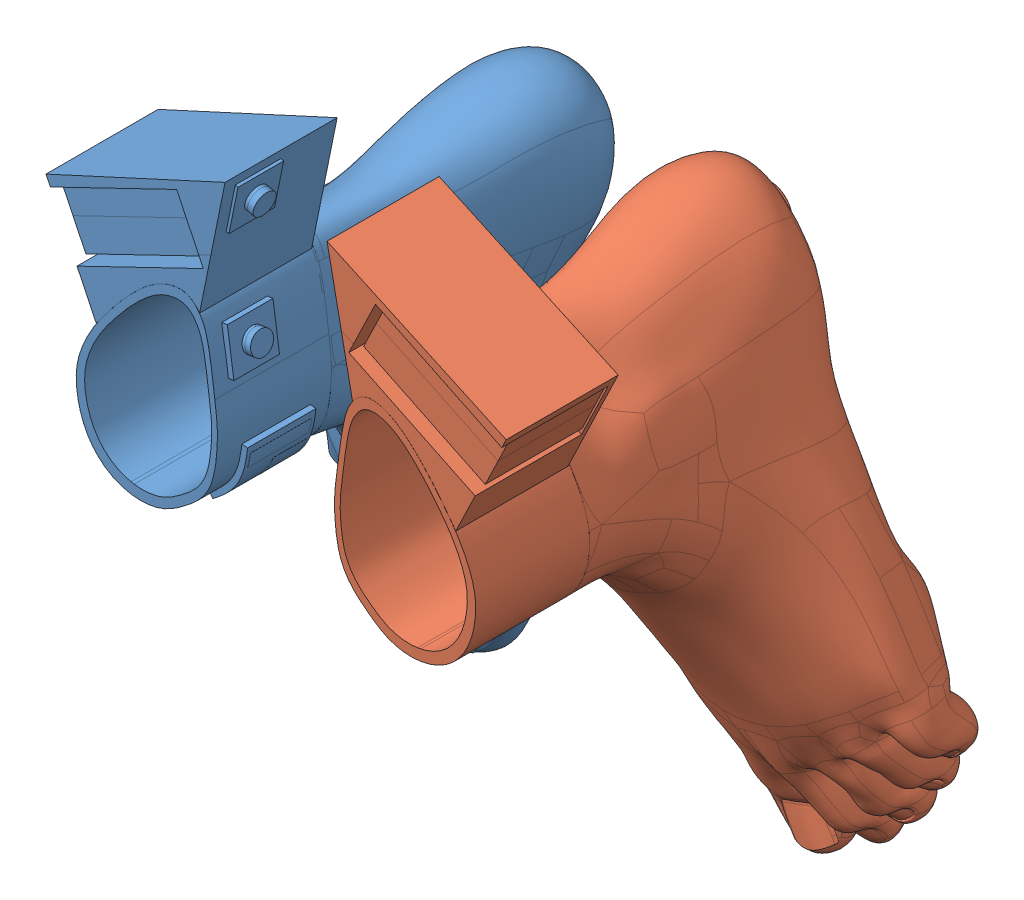
SolidWorks assembly Feet_plain2, configuration Default. Lengths in mm.
Overall size (546.46 568.46 358.41).
3 component instances, 3 part files, 0 mates.
Components (placement in the parent):
- foot1-1: foot1 [Right] at (256.4291 194.2322 323.4055) size (245.52 568.46 358.41)
- Mirrorfoot1-2: Mirrorfoot1 [Right] at (383.5709 194.2322 323.4055) x (-1 0 0) z (0 0 -1) (suppressed, hidden)
- Mirrorfoot1-4: Mirrorfoot1 [Right] at (223.5709 194.2322 323.4055) x (-1 0 0) z (0 0 -1) size (245.52 568.46 358.41)
